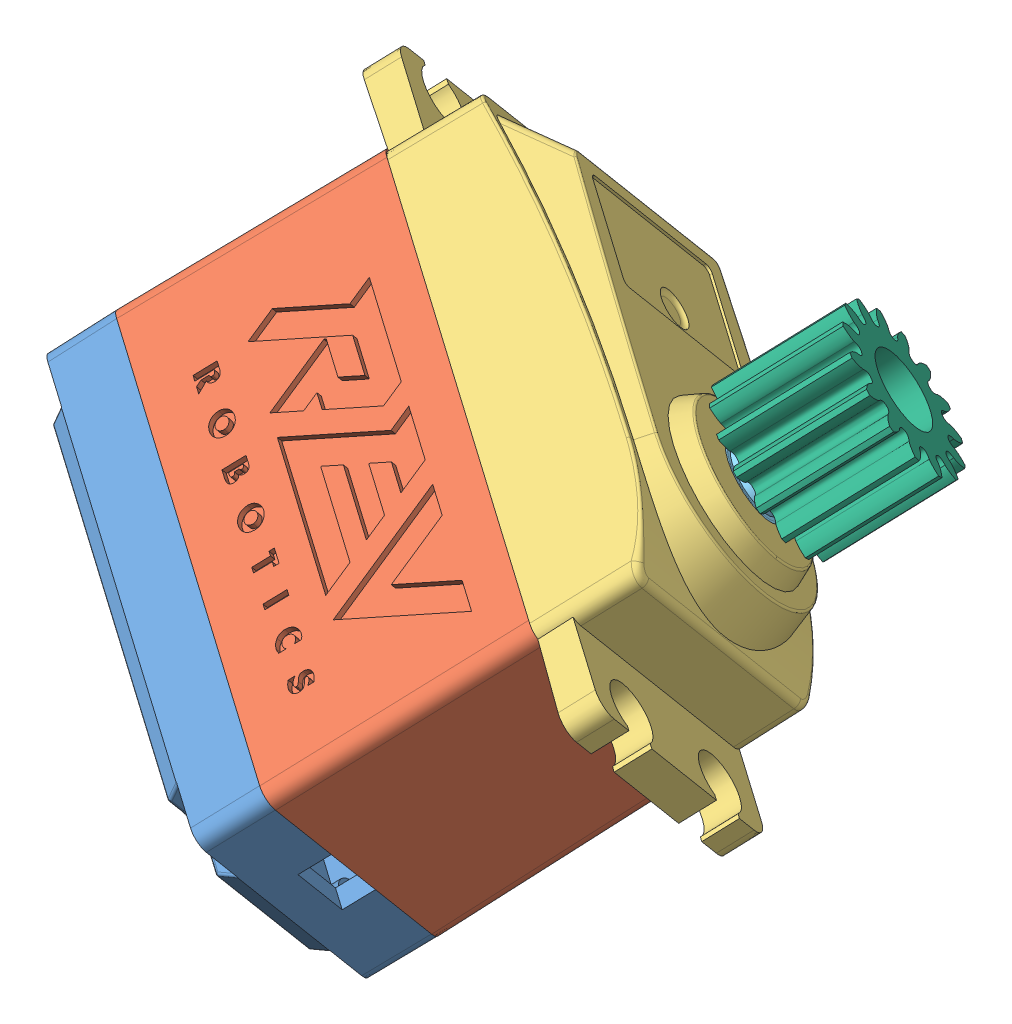
SolidWorks assembly ServoSmartRobotGear, configuration Default. Lengths in mm.
Overall size (71.23 55.45 66).
7 component instances, 6 part files, 3 mates.
Components (placement in the parent):
- PART_ASSEM_ServoSmartRobot-1: PART_ASSEM_ServoSmartRobot [Default] at (15.8472 5.8987 37.8782) x (0.134894 -0.768297 -0.625718) z (0.547325 0.584183 -0.599304) size (20.67 54 43.55) (flexible)
  - PART_ServoSmartRobot_A-1: PART_ServoSmartRobot_A [Default] at (14.1514 42.0466 -29.5827) x (-1 0 0) z (0 0 -1) size (20.15 40.13 8.5)
  - PART_ServoSmartRobot_E-1: PART_ServoSmartRobot_E [Default] at (14.1518 42.0362 -29.6327) x (-1 0 0) z (0 0 -1) size (20.24 40.15 20.1)
  - PART_ServoSmartRobot_C-1: PART_ServoSmartRobot_C [Default] at (14.1505 41.809 -29.6827) x (-1 0 0) z (0 0 -1) size (19.8 54 13.28)
  - PART_ServoSmartRobot_B-1: PART_ServoSmartRobot_B [Default] at (7.6026 39.3839 -29.6327) x (-0.758766 -0.651364 0) z (0 0 -1) size (9 9 4.4)
  - PART_ServoSmartRobot_D-1: PART_ServoSmartRobot_D [Default] at (14.1505 31.7564 0.3673) x (-0.973461 -0.228853 0) z (0 0 -1) size (17.2 17.19 14.7)
- PART_ServoSmartRobotGear_ServoGearAdapter-2: PART_ServoSmartRobotGear_ServoGearAdapter [Default] at (0.2652 12.6631 3.5984) x (-0.057713 -0.688033 -0.723381) z (-0.834928 0.430512 -0.342863) size (12.72 10 12.65)
Mates (geometry in assembly coordinates):
- Coincident5: coincident anti-aligned: plane of PART_ASSEM_ServoSmartRobot-1/PART_ServoSmartRobot_D-1 through (-0.8294 11.4947 4.797) normal (0.547325 0.584183 -0.599304); plane of PART_ServoSmartRobotGear_ServoGearAdapter-2 through (-0.8294 11.4947 4.797) normal (-0.547325 -0.584183 0.599304)
- Concentric2: concentric aligned: cylinder of PART_ASSEM_ServoSmartRobot-1/PART_ServoSmartRobot_D-1 through (-2.7259 9.4705 6.8736) axis (-0.547325 -0.584183 0.599304) radius 2.5; cylinder of PART_ServoSmartRobotGear_ServoGearAdapter-2 through (3.0019 15.584 0.6019) axis (-0.547325 -0.584183 0.599304) radius 3
- Coincident6: coincident anti-aligned: plane of PART_ASSEM_ServoSmartRobot-1/PART_ServoSmartRobot_D-1 through (-8.273 3.5498 12.9476) normal (0.057713 0.688033 0.723381); plane of PART_ServoSmartRobotGear_ServoGearAdapter-2 through (0.2652 12.6631 3.5984) normal (-0.057713 -0.688033 -0.723381)
